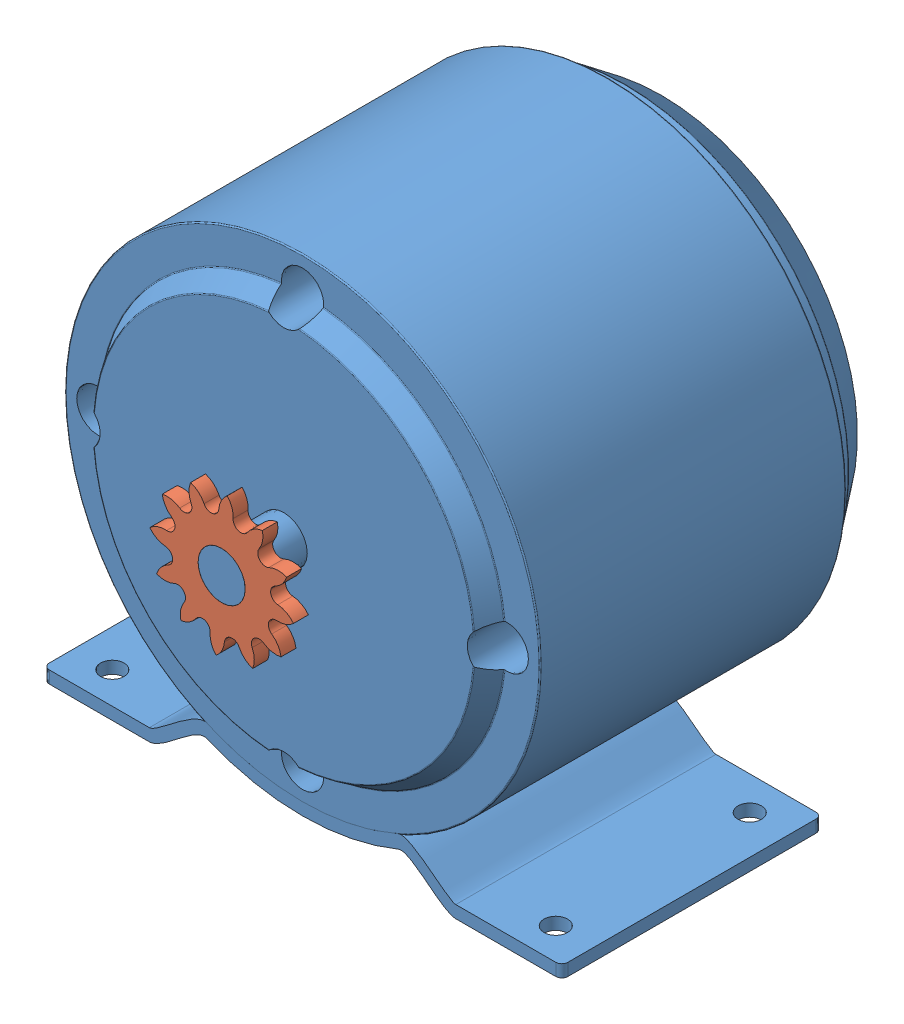
SolidWorks assembly scooter-motor-sprocket, configuration Default. Lengths in mm.
Overall size (110.2 106 103.2).
2 component instances, 2 part files, 2 mates.
Components (placement in the parent):
- scooter-motor-1: scooter-motor [Default] at (-35.1137 21.1152 -0.7179) size (110.2 106 103.2)
- sprocket-motor-12-1: sprocket-motor-12 [Default] at (-35.1137 21.1152 54.3071) x (-0.649992 0.759941 0) z (0 0 1) size (29.58 29.58 3.17)
Mates (geometry in assembly coordinates):
- Coincident1: coincident aligned: plane of scooter-motor-1 through (-35.1137 21.1152 57.4821) normal (0 0 1); plane of sprocket-motor-12-1 through (-23.6693 24.1819 57.4821) normal (0 0 1)
- Concentric1: concentric aligned: cylinder of scooter-motor-1 through (-35.1137 21.1152 57.4821) axis (0 0 -1) radius 5; cylinder of sprocket-motor-12-1 through (-35.1137 21.1152 57.4821) axis (0 0 -1) radius 5
